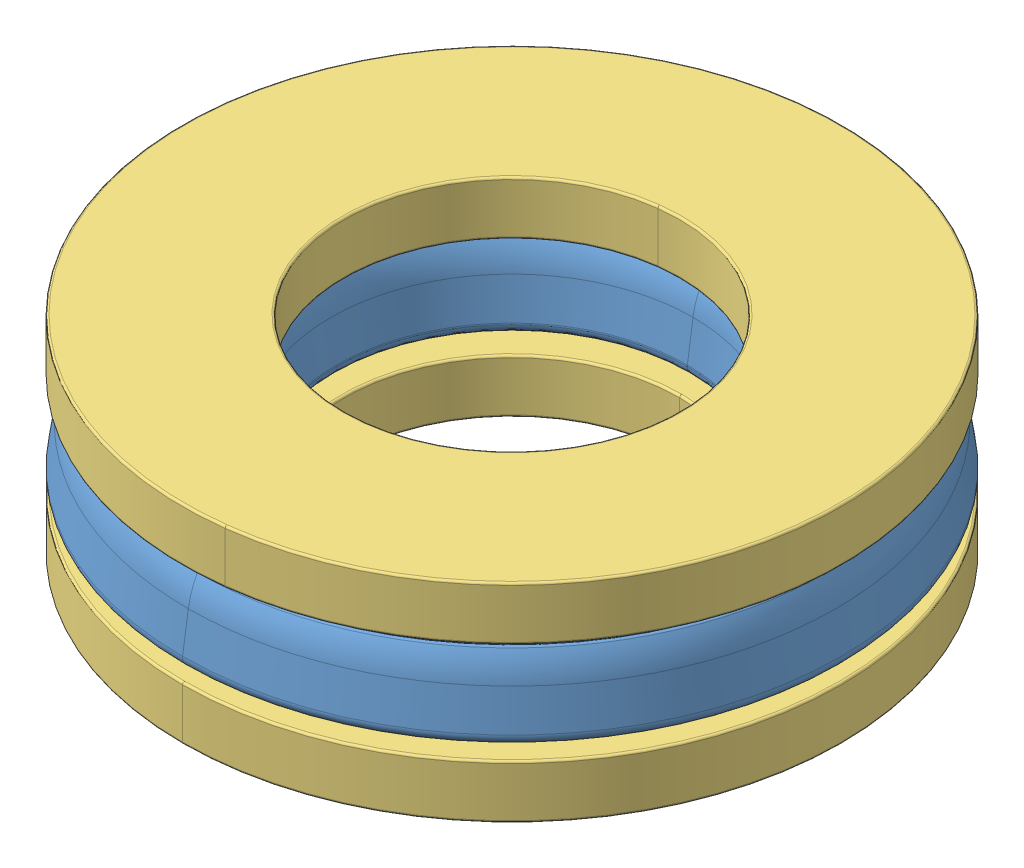
SolidWorks assembly 8mm thrust bearing (spacer), configuration Default. Lengths in mm.
Overall size (17.52 1.28 17.52).
13 component instances, 3 part files, 0 mates.
Components (placement in the parent):
- 1613-0516-0008.STEP-1: 1613-0516-0008.STEP [Default] at origin size (17.52 4.96 17.52)
  - 1613-0516-0008 carriage.STEP-1: 1613-0516-0008 carriage.STEP [Default] at (-23.0253 -4.8501 14.8236) size (15.72 1.83 15.72) (hidden)
  - 1613-0516-0008 ball.STEP-1: 1613-0516-0008 ball.STEP [Default] at (-28.8255 -3.9351 16.4353) size (3 3 3) (hidden)
  - 1613-0516-0008 ball.STEP-2: 1613-0516-0008 ball.STEP [Default] at (-26.4325 -3.9351 19.7866) x (0.766044 0 -0.642788) z (0.642788 0 0.766044) size (3 3 3) (hidden)
  - 1613-0516-0008 ball.STEP-3: 1613-0516-0008 ball.STEP [Default] at (-22.4452 -3.9351 20.8156) x (0.173648 0 -0.984808) z (0.984808 0 0.173648) size (3 3 3) (hidden)
  - 1613-0516-0008 ball.STEP-4: 1613-0516-0008 ball.STEP [Default] at (-18.7293 -3.9351 19.0408) x (-0.5 0 -0.866025) z (0.866025 0 -0.5) size (3 3 3) (hidden)
  - 1613-0516-0008 ball.STEP-5: 1613-0516-0008 ball.STEP [Default] at (-17.0236 -3.9351 15.2928) x (-0.939693 0 -0.34202) z (0.34202 0 -0.939693) size (3 3 3) (hidden)
  - 1613-0516-0008 ball.STEP-6: 1613-0516-0008 ball.STEP [Default] at (-18.1261 -3.9351 11.3252) x (-0.939693 0 0.34202) z (-0.34202 0 -0.939693) size (3 3 3) (hidden)
  - 1613-0516-0008 ball.STEP-7: 1613-0516-0008 ball.STEP [Default] at (-21.521 -3.9351 8.9945) x (-0.5 0 0.866025) z (-0.866025 0 -0.5) size (3 3 3) (hidden)
  - 1613-0516-0008 ball.STEP-8: 1613-0516-0008 ball.STEP [Default] at (-25.6197 -3.9351 9.3913) x (0.173648 0 0.984808) z (-0.984808 0 0.173648) size (3 3 3) (hidden)
  - 1613-0516-0008 ball.STEP-9: 1613-0516-0008 ball.STEP [Default] at (-28.5045 -3.9351 12.3299) x (0.766044 0 0.642788) z (-0.642788 0 0.766044) size (3 3 3) (hidden)
  - 1613-0516-0008 washer (8mm ID x 15.72mm OD).STEP-1: 1613-0516-0008 washer (8mm ID x 15.72mm OD).STEP [Default] at (-23.0253 -6.4151 14.8236) size (15.72 1.28 15.72) (hidden)
  - 1613-0516-0008 washer (8mm ID x 15.72mm OD).STEP-2: 1613-0516-0008 washer (8mm ID x 15.72mm OD).STEP [Default] at (-23.0253 -1.4551 14.8236) x (0.992523 0 -0.12206) z (-0.12206 0 -0.992523) size (15.72 1.28 15.72)
